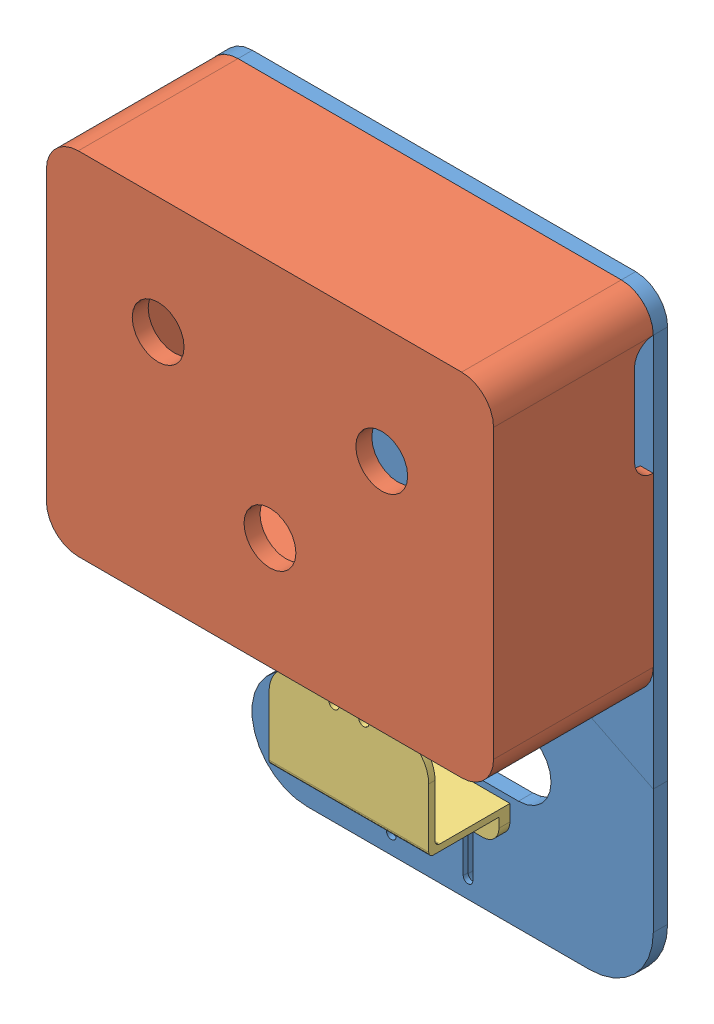
SolidWorks assembly Door Asembly, configuration Default. Lengths in mm.
Overall size (140 191.97 54.5).
3 component instances, 3 part files, 2 mates.
Components (placement in the parent):
- Backdoorbracket-2: Backdoorbracket [Default] at (13.5264 -31.0859 29.0996) size (140 191.97 4.5)
- buttoncase-3: buttoncase [Default] at (-28.7176 54.9936 83.5996) x (1 0 0) z (0 0 -1) size (140 110 50)
- servoBracket-1: servoBracket [Default] at (23.0195 -51.0149 33.0404) size (50 38 26)
Mates (geometry in assembly coordinates):
- Parallel3: parallel: line of Backdoorbracket-2 through (65.4578 -93.2753 33.0996) axis (0 1 0); line of buttoncase-3 through (63.8389 119.411 83.0996) axis (0 -1 0)
- Coincident8: coincident anti-aligned: plane of Backdoorbracket-2 through (53.8389 119.411 33.5996) normal (0 0 1); plane of buttoncase-3 through (-66.1611 119.411 33.5996) normal (0 0 -1)
